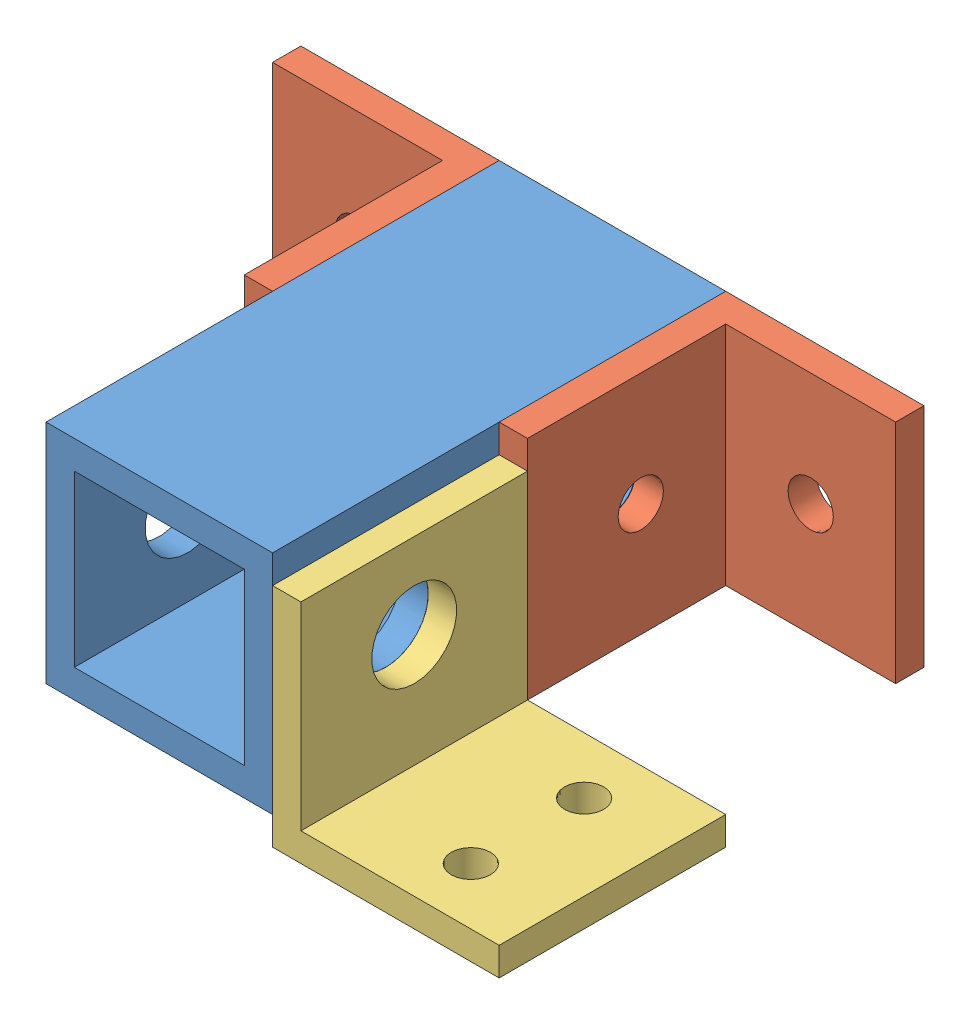
SolidWorks assembly Front Bumper Mount, configuration Default. Lengths in mm.
Overall size (76.2 28.58 50.8).
4 component instances, 3 part files, 9 mates.
Components (placement in the parent):
- Front Bumper Mount 1-1: Front Bumper Mount 1 [Default] at (24.8994 23.8958 12.2366) size (25.4 25.4 50.8)
- Front Bumper Mount 2-1: Front Bumper Mount 2 [Default] at (40.7744 23.8958 24.9366) x (0 -1 0) z (-1 0 0) size (25.4 25.4 25.4)
- Front Bumper Mount 2-2: Front Bumper Mount 2 [Default] at (9.0244 23.8958 24.9366) x (0 1 0) z (1 0 0) size (25.4 25.4 25.4)
- bumpber bracket-1: bumpber bracket [Front and back] at (37.5994 20.7208 50.3366) x (0 0 1) z (0 1 0) size (25.4 25.4 25.4)
Mates (geometry in assembly coordinates):
- Coincident1: coincident anti-aligned: plane of Front Bumper Mount 1-1 through (37.5994 11.1958 63.0366) normal (1 0 0); plane of Front Bumper Mount 2-1 through (37.5994 23.8958 24.9366) normal (-1 0 0)
- Concentric1: concentric aligned: cylinder of Front Bumper Mount 1-1 through (12.1994 23.8958 24.9366) axis (1 0 0) radius 2.4765; cylinder of Front Bumper Mount 2-1 through (37.5994 23.8958 24.9366) axis (1 0 0) radius 2.54
- Coincident2: coincident aligned: plane of Front Bumper Mount 1-1 through (24.8994 23.8958 12.2366) normal (0 0 -1); plane of Front Bumper Mount 2-1 through (37.5994 11.1958 12.2366) normal (0 0 -1)
- Concentric2: concentric anti-aligned: cylinder of Front Bumper Mount 1-1 through (12.1994 23.8958 24.9366) axis (1 0 0) radius 2.4765; cylinder of Front Bumper Mount 2-2 through (12.1994 23.8958 24.9366) axis (-1 0 0) radius 2.54
- Coincident3: coincident anti-aligned: plane of Front Bumper Mount 1-1 through (12.1994 11.1958 63.0366) normal (-1 0 0); plane of Front Bumper Mount 2-2 through (12.1994 23.8958 24.9366) normal (1 0 0)
- Coincident4: coincident aligned: plane of Front Bumper Mount 1-1 through (24.8994 23.8958 12.2366) normal (0 0 -1); plane of Front Bumper Mount 2-2 through (12.1994 36.5958 12.2366) normal (0 0 -1)
- Coincident5: coincident anti-aligned: plane of Front Bumper Mount 1-1 through (37.5994 11.1958 63.0366) normal (1 0 0); plane of bumpber bracket-1 through (37.5994 20.7208 50.3366) normal (-1 0 0)
- Concentric4: concentric aligned: circle of Front Bumper Mount 1-1; cylinder of bumpber bracket-1 through (37.5994 23.8958 50.3366) axis (1 0 0) radius 4.7625
- Parallel1: parallel aligned: plane of Front Bumper Mount 1-1 through (12.1994 36.5958 63.0366) normal (0 1 0); plane of bumpber bracket-1 through (40.7744 33.4208 37.6366) normal (0 1 0)
